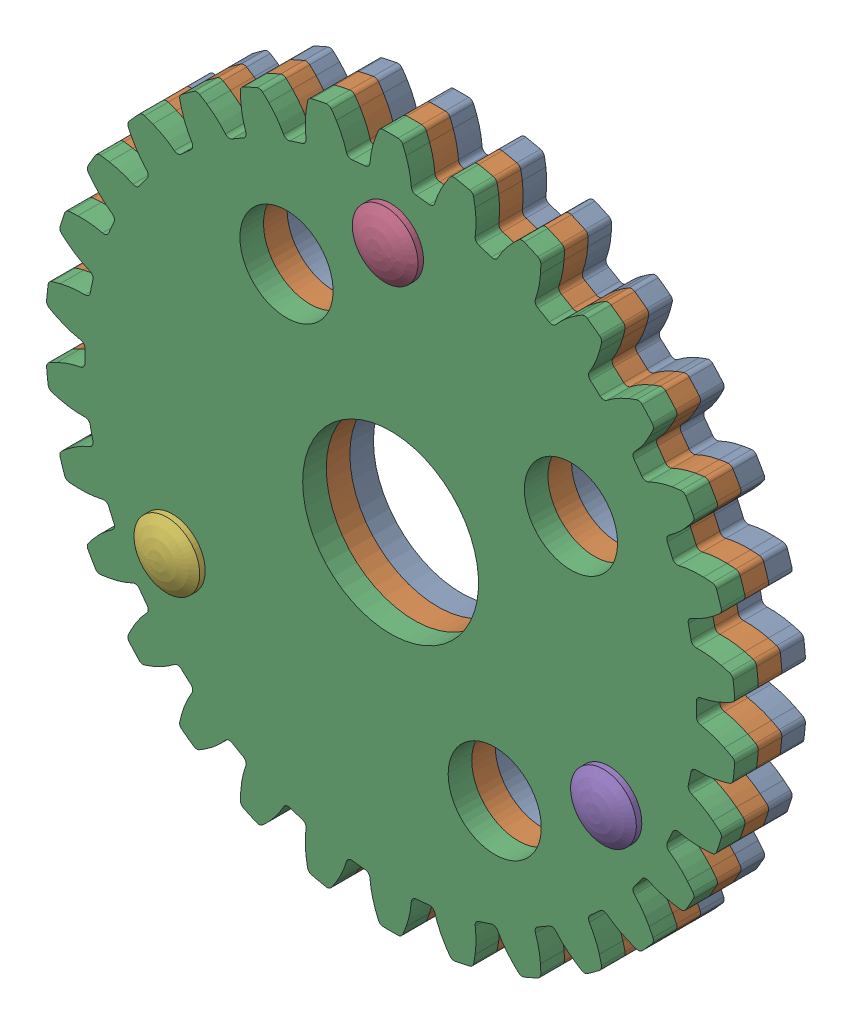
SolidWorks assembly 304395 Tooth Gear Assembly, configuration Predeterminado. Lengths in mm.
Overall size (99.67 100.01 13.42).
6 component instances, 2 part files, 0 mates.
Components (placement in the parent):
- 404443 30T Gear-1: 404443 30T Gear [Predeterminado] at origin size (99.67 100.01 3.42)
- 404443 30T Gear-2: 404443 30T Gear [Predeterminado] at (0 0 3.4163) size (99.67 100.01 3.42)
- 404443 30T Gear-3: 404443 30T Gear [Predeterminado] at (0 0 6.8326) size (99.67 100.01 3.42)
- 206078 Rivit-1: 206078 Rivit [Predeterminado] at (0 36.5125 12.6289) x (0 0 -1) z (-0.029007 -0.999579 0) size (13.42 9.53 9.53)
- 206078 Rivit-2: 206078 Rivit [Predeterminado] at (31.6208 -18.2563 12.6289) x (0 0 -1) z (0.972835 0.231501 0) size (13.42 9.53 9.53)
- 206078 Rivit-3: 206078 Rivit [Predeterminado] at (-31.6208 -18.2563 12.6289) x (0 0 -1) z (-0.172822 0.984953 0) size (13.42 9.53 9.53)
